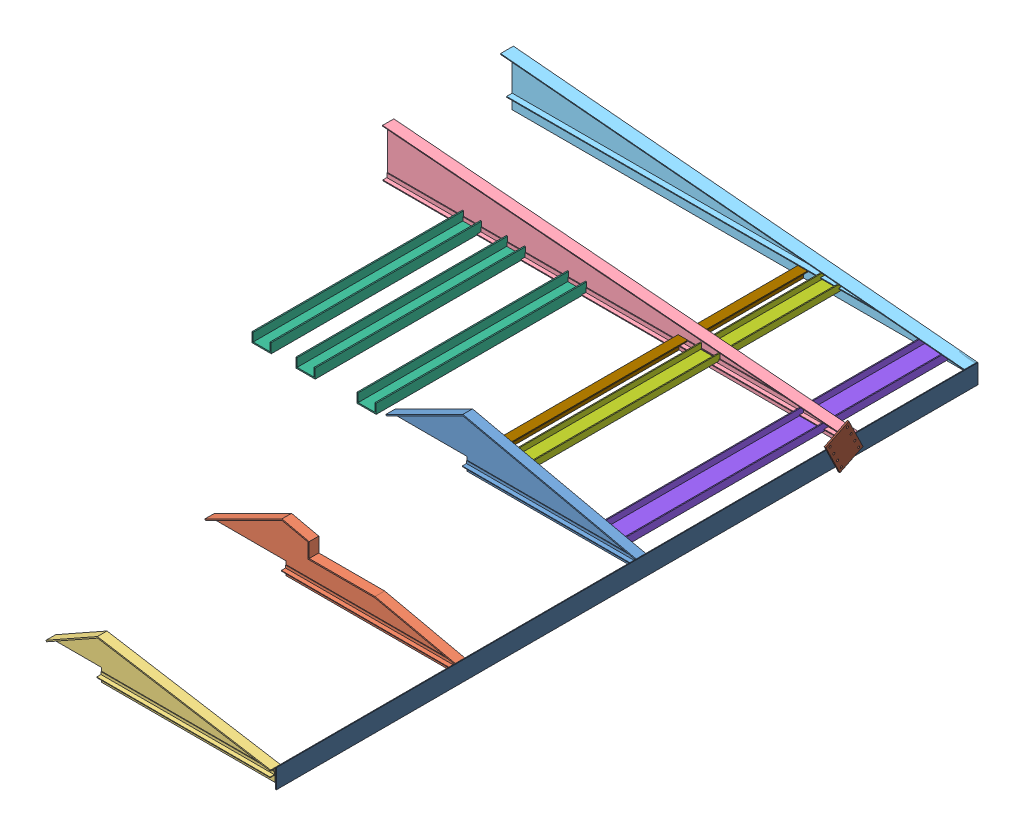
SolidWorks assembly _2015-12-07 LIVING DECK (FR 323.33), configuration Default. Lengths in mm.
Overall size (3689.92 526.99 5595.94).
13 component instances, 11 part files, 40 mates.
Components (placement in the parent):
- JOIST 1-1: JOIST 1 [Default] at (2298.7 0 -1308.1) x (0 -1 0) z (0 0 -1) size (406.4 1981.2 85.72)
- JOIST 2-1: JOIST 2 [Default] at (2298.7 0 123.825) x (0 -1 0) z (0 0 -1) size (406.4 1981.2 85.72)
- JOIST 3-1: JOIST 3 [Default] at (2298.7 0 1584.325) x (0 -1 0) z (0 0 -1) size (330.2 1778 85.72)
- JOIST 4-1: JOIST 4 [Default] at (0 0 -2978.15) x (0 -1 0) z (0 0 -1) size (406.4 3670.83 88.9)
- JOIST 5-1: JOIST 5 [Default] at (0 0 -3968.75) x (0 -1 0) z (0 0 -1) size (431.8 3670.87 101.6)
- C_9-11-15_SECTION H-H-1: C_9-11-15_SECTION H-H [Default] at (668.02 25.4 -1308.1) x (0 1 0) z (0 0 1) size (76.2 152.4 1670.05)
- C_9-11-15_SECTION H-H-2: C_9-11-15_SECTION H-H [Default] at (1016 25.4 -1308.1) x (0 1 0) z (0 0 1) size (76.2 152.4 1670.05)
- C_9-11-15_SECTION H-H-3: C_9-11-15_SECTION H-H [Default] at (1498.6 25.4 -1308.1) x (0 1 0) z (0 0 1) size (76.2 152.4 1670.05)
- C_9-11-15_SECTION I-I-1: C_9-11-15_SECTION I-I [Default] at (2552.7 88.9 -1308.1) x (0 1 0) z (0 0 1) size (50.8 152.4 2660.65)
- C_9-11-15_SECTION J-J-1: C_9-11-15_SECTION J-J [Default] at (3390.9 55.5625 -1308.1) x (0 1 0) z (0 0 1) size (57.15 203.2 2660.65)
- L_9-11-15_SECTION A-A-1: L_9-11-15_SECTION A-A [Default] at (2298.7 101.6 -1308.1) x (0 1 0) z (0 0 -1) size (101.6 76.2 2660.65)
- PLATE_9-11-15_SECTION B-B-1: PLATE_9-11-15_SECTION B-B [Default] at (3670.3 101.6 1584.325) x (0 1 0) z (0 0 1) size (152.4 6.35 5553.07)
- BOLTING PLATE_9-15-15-2: BOLTING PLATE_9-15-15 [Default] at (3676.65 63.5 -2898.775) x (1 0 0) z (0 0.438371 -0.898794) size (12.7 254 203.2)
Mates (geometry in assembly coordinates):
- Coincident1: coincident anti-aligned: plane of JOIST 1-1; plane of assembly through (0 0 0) normal (0 1 0)
- Coincident6: coincident anti-aligned: plane of JOIST 1-1; plane of assembly through (2298.7 0 0) normal (1 0 0)
- Distance2: distance = 1308.1 mm anti-aligned: plane of assembly through (0 0 0) normal (0 0 1); plane of JOIST 1-1 through (2298.7 0 -1308.1) normal (0 0 -1)
- Coincident8: coincident anti-aligned: plane of JOIST 3-1; plane of assembly through (2298.7 0 0) normal (1 0 0)
- Coincident9: coincident anti-aligned: plane of JOIST 3-1; plane of assembly through (0 0 0) normal (0 1 0)
- Distance3: distance = 2892.425 mm aligned: plane of JOIST 3-1 through (2298.7 0 1584.325) normal (0 0 -1); plane of JOIST 1-1 through (2298.7 0 -1308.1) normal (0 0 -1)
- Coincident11: coincident anti-aligned: plane of JOIST 2-1; plane of assembly through (2298.7 0 0) normal (1 0 0)
- Coincident12: coincident anti-aligned: plane of JOIST 2-1; plane of assembly through (0 0 0) normal (0 1 0)
- Distance4: distance = 1431.925 mm aligned: plane of JOIST 1-1 through (2298.7 0 -1308.1) normal (0 0 -1); plane of JOIST 2-1 through (2298.7 0 123.825) normal (0 0 -1)
- Coincident14: coincident anti-aligned: plane of JOIST 4-1; plane of assembly through (0 0 0) normal (1 0 0)
- Coincident15: coincident anti-aligned: plane of JOIST 4-1; plane of assembly through (0 0 0) normal (0 1 0)
- Distance5: distance = 1670.05 mm aligned: plane of JOIST 4-1 through (0 0 -2978.15) normal (0 0 -1); plane of JOIST 1-1 through (2298.7 0 -1308.1) normal (0 0 -1)
- Coincident17: coincident anti-aligned: plane of JOIST 5-1; plane of assembly through (0 0 0) normal (1 0 0)
- Coincident18: coincident anti-aligned: plane of JOIST 5-1; plane of assembly through (0 0 0) normal (0 1 0)
- Distance6: distance = 2660.65 mm aligned: plane of JOIST 5-1 through (0 0 -3968.75) normal (0 0 -1); plane of JOIST 1-1 through (2298.7 0 -1308.1) normal (0 0 -1)
- Coincident19: coincident anti-aligned: plane of JOIST 1-1 through (2298.7 0 -1308.1) normal (0 0 -1); plane of C_9-11-15_SECTION H-H-1 through (668.02 25.4 -1308.1) normal (0 0 1)
- Distance7: distance = 25.4 mm aligned: plane of C_9-11-15_SECTION H-H-1; plane of assembly through (0 0 0) normal (0 1 0)
- Distance8: distance = 668.02 mm anti-aligned: plane of C_9-11-15_SECTION H-H-1; plane of assembly through (0 0 0) normal (1 0 0)
- Coincident22: coincident anti-aligned: plane of JOIST 1-1 through (2298.7 0 -1308.1) normal (0 0 -1); plane of C_9-11-15_SECTION H-H-2 through (1016 25.4 -1308.1) normal (0 0 1)
- Distance9: distance = 25.4 mm aligned: plane of C_9-11-15_SECTION H-H-2; plane of assembly through (0 0 0) normal (0 1 0)
- Distance10: distance = 1016 mm anti-aligned: plane of C_9-11-15_SECTION H-H-2; plane of assembly through (0 0 0) normal (1 0 0)
- Coincident25: coincident anti-aligned: plane of JOIST 1-1 through (2298.7 0 -1308.1) normal (0 0 -1); plane of C_9-11-15_SECTION H-H-3 through (1498.6 25.4 -1308.1) normal (0 0 1)
- Distance11: distance = 25.4 mm aligned: plane of C_9-11-15_SECTION H-H-3; plane of assembly through (0 0 0) normal (0 1 0)
- Distance12: distance = 1498.6 mm anti-aligned: plane of C_9-11-15_SECTION H-H-3; plane of assembly through (0 0 0) normal (1 0 0)
- Coincident28: coincident anti-aligned: plane of JOIST 1-1 through (2298.7 0 -1308.1) normal (0 0 -1); plane of C_9-11-15_SECTION I-I-1 through (2552.7 88.9 -1308.1) normal (0 0 1)
- Distance13: distance = 88.9 mm aligned: plane of C_9-11-15_SECTION I-I-1; plane of assembly through (0 0 0) normal (0 1 0)
- Distance14: distance = 2552.7 mm anti-aligned: plane of C_9-11-15_SECTION I-I-1; plane of assembly through (0 0 0) normal (1 0 0)
- Coincident31: coincident anti-aligned: plane of JOIST 1-1 through (2298.7 0 -1308.1) normal (0 0 -1); plane of C_9-11-15_SECTION J-J-1 through (3390.9 55.5625 -1308.1) normal (0 0 1)
- Distance15: distance = 55.5625 mm aligned: plane of assembly through (0 0 0) normal (0 1 0); plane of C_9-11-15_SECTION J-J-1
- Distance16: distance = 3390.9 mm anti-aligned: plane of assembly through (0 0 0) normal (1 0 0); plane of C_9-11-15_SECTION J-J-1
- Coincident34: coincident aligned: plane of JOIST 1-1 through (2298.7 0 -1308.1) normal (0 0 -1); plane of L_9-11-15_SECTION A-A-1 through (2298.7 101.6 -1308.1) normal (0 0 -1)
- Distance17: distance = 2298.7 mm aligned: plane of L_9-11-15_SECTION A-A-1; plane of assembly through (0 0 0) normal (1 0 0)
- Distance18: distance = 101.6 mm aligned: plane of assembly through (0 0 0) normal (0 1 0); plane of L_9-11-15_SECTION A-A-1
- Distance19: distance = 3670.3 mm anti-aligned: plane of assembly through (0 0 0) normal (1 0 0); plane of PLATE_9-11-15_SECTION B-B-1
- Coincident38: coincident anti-aligned: plane of JOIST 3-1 through (2298.7 0 1584.325) normal (0 0 -1); plane of PLATE_9-11-15_SECTION B-B-1 through (3670.3 101.6 1584.325) normal (0 0 1)
- Distance20: distance = 101.6 mm aligned: plane of assembly through (0 0 0) normal (0 1 0); plane of PLATE_9-11-15_SECTION B-B-1
- Distance24: distance = 3676.65 mm aligned: plane of BOLTING PLATE_9-15-15-2; plane of assembly through (0 0 0) normal (1 0 0)
- Distance25: distance = 63.5 mm: point of BOLTING PLATE_9-15-15-2; plane of assembly
- Distance27: distance = 79.375 mm: plane of JOIST 4-1 through (0 0 -2978.15) normal (0 0 -1); point of BOLTING PLATE_9-15-15-2
- Angle2: planar angle = 0.453786 rad aligned: plane of JOIST 4-1 through (0 0 -2978.15) normal (0 0 -1); plane of BOLTING PLATE_9-15-15-2 through (3676.65 63.5 -2898.775) normal (0 0.438371 -0.898794)
